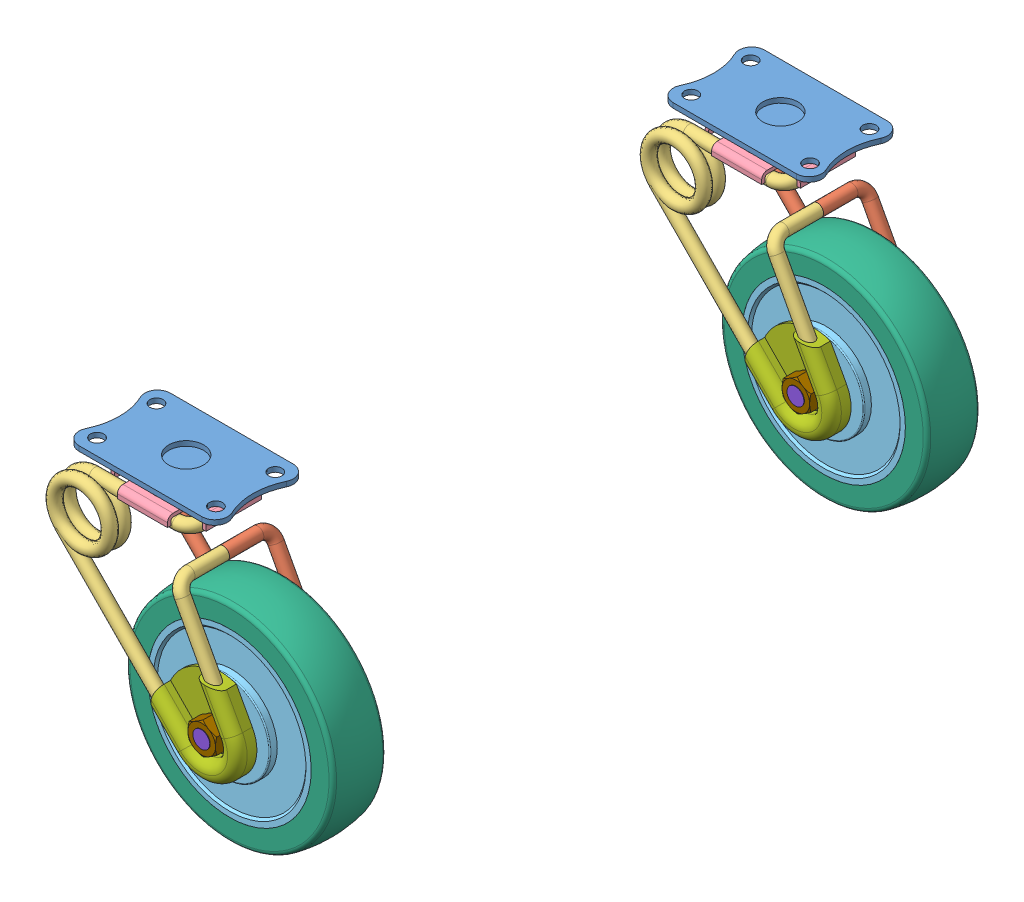
SolidWorks assembly Assem2, configuration ﾃﾞﾌｫﾙﾄ. Lengths in mm.
Overall size (125.88 136.72 333.61).
26 component instances, 9 part files, 3 mates.
Components (placement in the parent):
- SUSAJ-TS6-100-1: SUSAJ-TS6-100 [ﾃﾞﾌｫﾙﾄ] at (-17.0418 95.0523 65.2753) size (125.88 136.72 53.61)
  - table1-1: table1 [ﾃﾞﾌｫﾙﾄ] at (4.6677 7.0382 70) size (70 6.3 43)
  - spring-1: spring [ﾃﾞﾌｫﾙﾄ] at (-22.2933 -17.0618 54) x (1 0 0) z (0 1 0) size (91.52 25.65 92.48)
  - spring_mirror-1: spring_mirror [ﾃﾞﾌｫﾙﾄ] at (-22.2933 -17.0618 54) x (1 0 0) z (0 1 0) size (91.42 25.65 92.38)
  - table2-1: table2 [ﾃﾞﾌｫﾙﾄ] at (4.6677 -4.1618 70) size (44.8 7.2 41.2)
  - caster_wheel-1: caster_wheel [ﾃﾞﾌｫﾙﾄ] at (-62.4157 -78.3589 65.5546) x (0 0 -1) z (1 0 0) size (30 100 100)
    - wheel_plate-1: wheel_plate [ﾃﾞﾌｫﾙﾄ] at (-16.9454 0.9806 100) x (0 -1 0) z (0 0 1) size (77 30 77)
    - caster_tire-1: caster_tire [ﾃﾞﾌｫﾙﾄ] at (-4.4454 0.9806 100) size (25 100 100)
  - cover-1: cover [ﾃﾞﾌｫﾙﾄ] at (37.5843 -77.3783 52.8) x (-1 0 0) z (0 -1 0) size (41.2 9.61 41.21)
  - cover-2: cover [ﾃﾞﾌｫﾙﾄ] at (37.5843 -77.3783 87.2) x (0.28881 0.957386 0) z (0.957386 -0.28881 0) size (41.2 9.61 41.21)
  - bar-1: bar [ﾃﾞﾌｫﾙﾄ] at (37.5843 -77.3783 44.2) x (1 0 0) z (0 -1 0) size (8 51.6 8)
  - hexagon nut style 1_ab_jis-1: hexagon nut style 1_ab_jis [JIS B 1181 Hexagon nut - style 1 A M8 - W --N] at (37.5843 -77.3783 44.4) x (-0.923728 -0.383049 0) z (0 0 -1) size (13 15.01 6.8)
  - hexagon nut style 1_ab_jis-2: hexagon nut style 1_ab_jis [JIS B 1181 Hexagon nut - style 1 A M8 - W --N] at (37.5843 -77.3783 95.6) size (13 15.01 6.8)
- SUSAJ-TS6-100-2: SUSAJ-TS6-100 [ﾃﾞﾌｫﾙﾄ] at (-17.0418 95.0523 -214.7247) size (125.88 136.72 53.61)
  - table1-1: table1 [ﾃﾞﾌｫﾙﾄ] at (4.6677 7.0382 70) size (70 6.3 43)
  - spring-1: spring [ﾃﾞﾌｫﾙﾄ] at (-22.2933 -17.0618 54) x (1 0 0) z (0 1 0) size (91.52 25.65 92.48)
  - spring_mirror-1: spring_mirror [ﾃﾞﾌｫﾙﾄ] at (-22.2933 -17.0618 54) x (1 0 0) z (0 1 0) size (91.42 25.65 92.38)
  - table2-1: table2 [ﾃﾞﾌｫﾙﾄ] at (4.6677 -4.1618 70) size (44.8 7.2 41.2)
  - caster_wheel-1: caster_wheel [ﾃﾞﾌｫﾙﾄ] at (-62.4157 -78.3589 65.5546) x (0 0 -1) z (1 0 0) size (30 100 100)
    - wheel_plate-1: wheel_plate [ﾃﾞﾌｫﾙﾄ] at (-16.9454 0.9806 100) x (0 -1 0) z (0 0 1) size (77 30 77)
    - caster_tire-1: caster_tire [ﾃﾞﾌｫﾙﾄ] at (-4.4454 0.9806 100) size (25 100 100)
  - cover-1: cover [ﾃﾞﾌｫﾙﾄ] at (37.5843 -77.3783 52.8) x (-1 0 0) z (0 -1 0) size (41.2 9.61 41.21)
  - cover-2: cover [ﾃﾞﾌｫﾙﾄ] at (37.5843 -77.3783 87.2) x (0.28881 0.957386 0) z (0.957386 -0.28881 0) size (41.2 9.61 41.21)
  - bar-1: bar [ﾃﾞﾌｫﾙﾄ] at (37.5843 -77.3783 44.2) x (1 0 0) z (0 -1 0) size (8 51.6 8)
  - hexagon nut style 1_ab_jis-1: hexagon nut style 1_ab_jis [JIS B 1181 Hexagon nut - style 1 A M8 - W --N] at (37.5843 -77.3783 44.4) x (-0.923728 -0.383049 0) z (0 0 -1) size (13 15.01 6.8)
  - hexagon nut style 1_ab_jis-2: hexagon nut style 1_ab_jis [JIS B 1181 Hexagon nut - style 1 A M8 - W --N] at (37.5843 -77.3783 95.6) size (13 15.01 6.8)
Mates (geometry in assembly coordinates):
- 一致1: coincident: plane of SUSAJ-TS6-100-1/table1-1 through (-12.3741 104.3905 135.2753) normal (0 1 0); plane of SUSAJ-TS6-100-2/table1-1 through (-12.3741 104.3905 89.4757) normal (0 1 0)
- 同心円1: concentric: cylinder of SUSAJ-TS6-100-1/caster_wheel-1/wheel_plate-1 through (20.5425 17.6739 150.2753) axis (0 0 -1) radius 21.5; cylinder of SUSAJ-TS6-100-2/caster_wheel-1/wheel_plate-1 through (20.5425 17.6739 104.4757) axis (0 0 -1) radius 21.5
- 距離1: distance = 237 mm anti-aligned: plane of SUSAJ-TS6-100-2/table1-1 through (-12.3741 104.3905 -123.2247) normal (0 0 1); plane of SUSAJ-TS6-100-1/table1-1 through (-12.3741 104.3905 113.7753) normal (0 0 -1)
